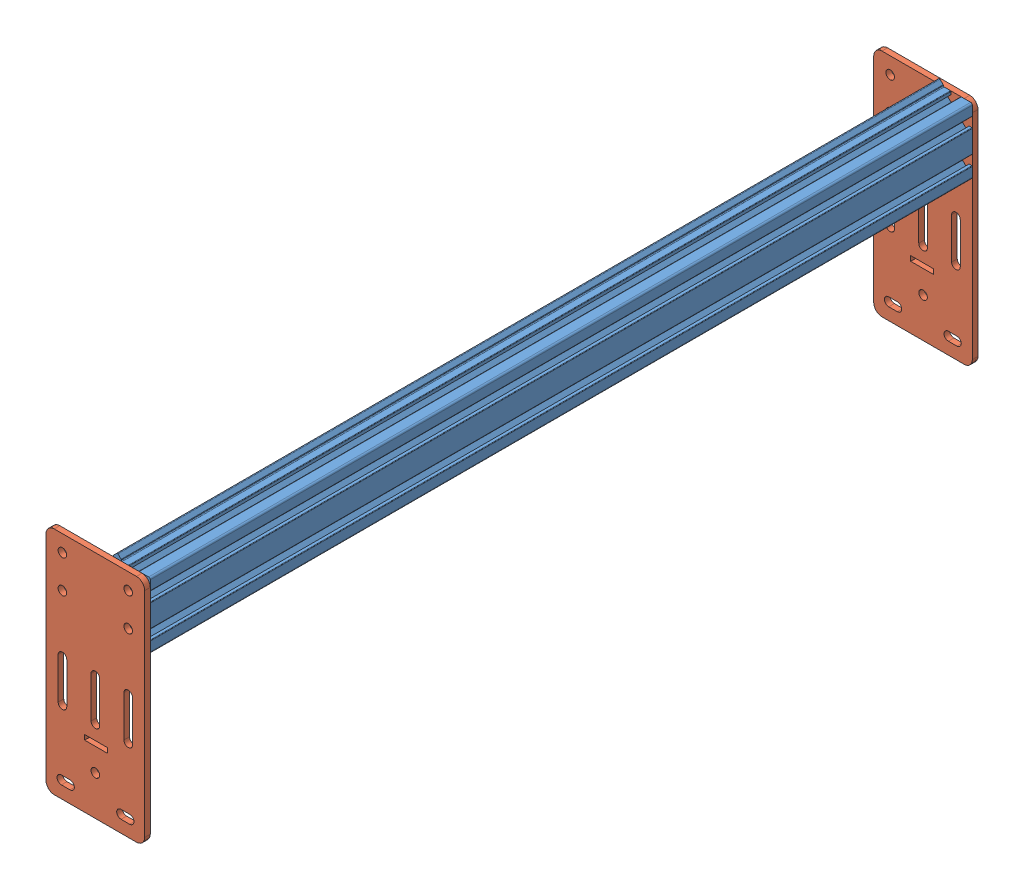
SolidWorks assembly Y_Axis_Left, configuration Default. Lengths in mm.
Overall size (60 142.97 506.83).
3 component instances, 2 part files, 9 mates.
Components (placement in the parent):
- 25142-XX500-1: 25142-XX500 [Default] x (-1 0 0) z (0 0 1) size (22.38 45.94 500)
- 26028-01-1: 26028-01 [Default] at (-20 -50 103.4163) x (1 0 0) z (0 0 -1) size (60 140 3.42)
- 26028-01-2: 26028-01 [Default] at (-20 -50 -403.4163) x (-1 0 0) z (0 0 1) size (60 140 3.42)
Mates (geometry in assembly coordinates):
- Coincident1: coincident: plane of 25142-XX500-1 through (0 0 0) normal (0 0 1); plane of assembly
- Coincident2: coincident: plane of 25142-XX500-1; plane of assembly
- Coincident3: coincident: plane of 25142-XX500-1; plane of assembly
- Concentric1: concentric: cylinder of 25142-XX500-1 through (0 10 100) axis (0 0 -1) radius 2.505; cylinder of 26028-01-1 through (0 10 100) axis (0 0 1) radius 2.625
- Concentric2: concentric: cylinder of 25142-XX500-1 through (0 -10 100) axis (0 0 -1) radius 2.505; cylinder of 26028-01-1 through (0 -10 100) axis (0 0 1) radius 2.625
- Coincident4: coincident anti-aligned: plane of 25142-XX500-1 through (0 0 100) normal (0 0 1); plane of 26028-01-1 through (-20 -50 100) normal (0 0 -1)
- Concentric3: concentric: cylinder of 25142-XX500-1 through (0 10 100) axis (0 0 -1) radius 2.505; cylinder of 26028-01-2 through (0 10 -400) axis (0 0 -1) radius 2.625
- Concentric4: concentric: cylinder of 25142-XX500-1 through (0 -10 100) axis (0 0 -1) radius 2.505; cylinder of 26028-01-2 through (0 -10 -400) axis (0 0 -1) radius 2.625
- Coincident5: coincident anti-aligned: plane of 25142-XX500-1 through (-0.3057 -0.8501 -400) normal (0 0 -1); plane of 26028-01-2 through (-20 -50 -400) normal (0 0 1)
